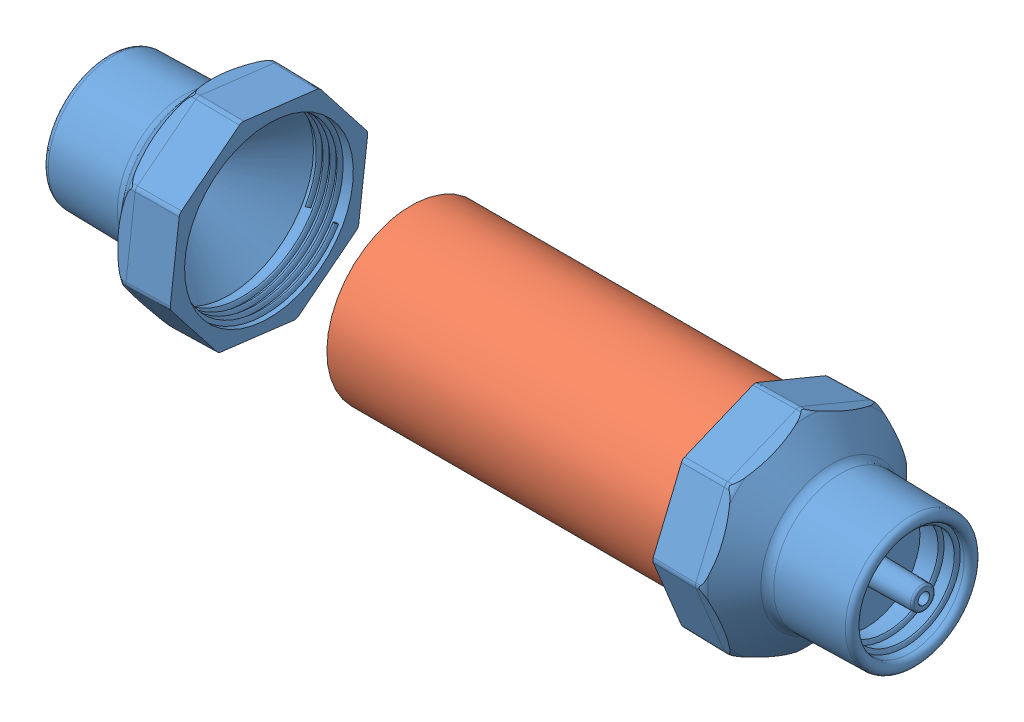
SolidWorks assembly filter, configuration Default. Lengths in mm.
Overall size (214.71 75.24 75.24).
3 component instances, 2 part files, 5 mates.
Components (placement in the parent):
- multi-adapter-1: multi-adapter [Défaut] at (14.4962 6.6222 -1.3608) size (44 55.22 55.22)
- tube-1: tube [Default] at (-17.1172 6.6222 -1.3608) x (0 0.983291 0.182041) z (-1 0 0) size (44 44 100)
- multi-adapter-2: multi-adapter [Défaut] at (-196.2091 6.6222 -1.3608) x (-1 0 0) z (0 0.49207 0.870556) size (44 55.22 55.22)
Mates (geometry in assembly coordinates):
- Concentric1: concentric aligned: cylinder of multi-adapter-1 through (14.4962 6.6222 -1.3608) axis (1 0 0) radius 22; cylinder of tube-1 through (-117.1172 6.6222 -1.3608) axis (1 0 0) radius 22
- Coincident1: coincident aligned: circle of multi-adapter-1; plane of tube-1 through (-17.1172 6.6222 -1.3608) normal (1 0 0)
- Concentric2: concentric: cylinder of tube-1 through (-117.1172 6.6222 -1.3608) axis (1 0 0) radius 22; cylinder of multi-adapter-2 through (-196.2091 6.6222 -1.3608) axis (-1 0 0) radius 22
- Coincident2: coincident aligned: plane of tube-1 through (-117.1172 6.6222 -1.3608) normal (-1 0 0); circle of multi-adapter-2
- Distance1: distance = 37.0918 mm anti-aligned: plane of multi-adapter-2 through (-154.2091 -6.6637 -24.8658) normal (1 0 0); plane of tube-1 through (-117.1172 6.6222 -1.3608) normal (-1 0 0)
